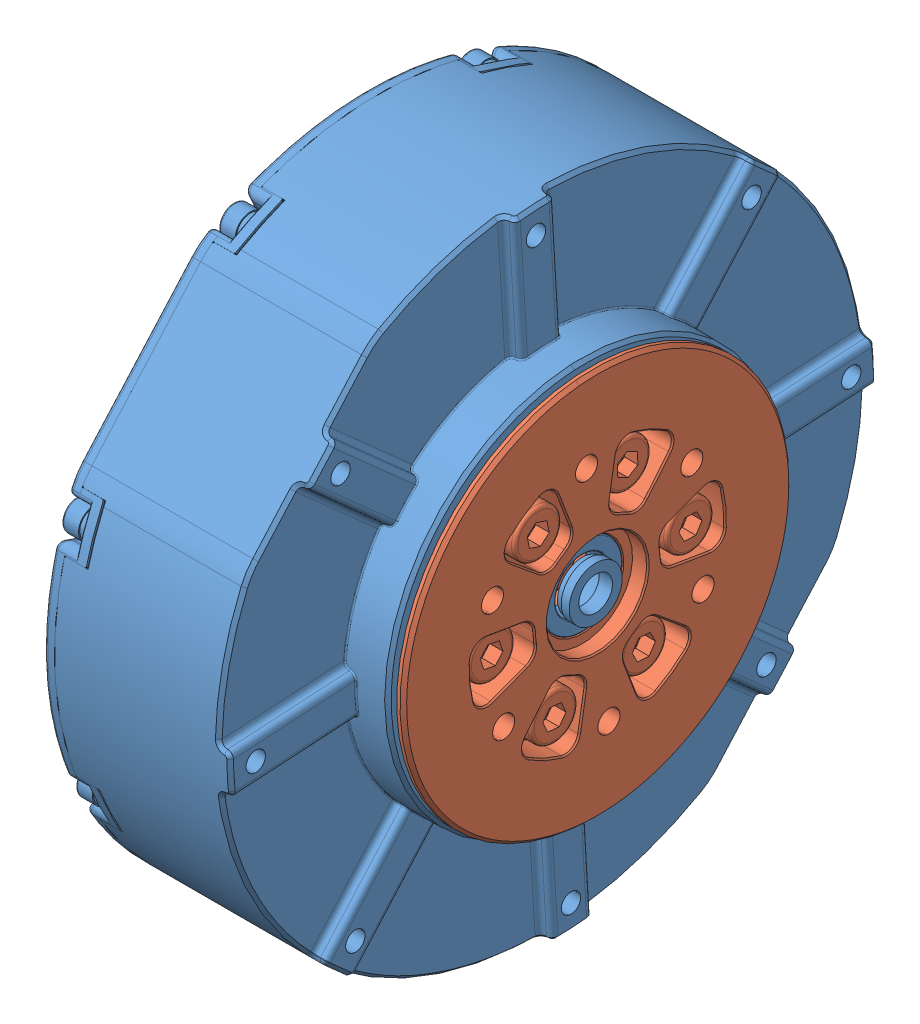
SolidWorks assembly 宇树电机-可转动, configuration 默认. Lengths in mm.
Overall size (42.3 98.68 99.96).
2 component instances, 2 part files, 6 mates.
Components (placement in the parent):
- GO-M8010-6电机3D模型-定子-1: GO-M8010-6电机3D模型-定子 [默认] at origin size (42 98.68 99.96)
- GO-M8010-6电机3D模型-转子-1: GO-M8010-6电机3D模型-转子 [默认] at (105.0963 -178.1437 7.2087) x (1 0 0) z (0 -0.975139 0.221594) size (8.3 59.93 59.79)
Mates (geometry in assembly coordinates):
- 同心1: concentric aligned: circle of GO-M8010-6电机3D模型-定子-1; circle of GO-M8010-6电机3D模型-转子-1
- 距离1: distance = 0.3 mm anti-aligned: plane of GO-M8010-6电机3D模型-定子-1 through (112.4454 -227.1803 -38.815) normal (1 0 0); plane of GO-M8010-6电机3D模型-转子-1 through (112.7454 -135.2106 33.605) normal (-1 0 0)
- 重合4: coincident aligned: plane of GO-M8010-6电机3D模型-定子-1 through (0 0 0) normal (0 0 1)
- 重合5: coincident aligned: plane of GO-M8010-6电机3D模型-定子-1 through (0 0 0) normal (0 1 0)
- 重合6: coincident aligned: plane of GO-M8010-6电机3D模型-定子-1 through (0 0 0) normal (1 0 0)
- 重合7: coordinate: point of GO-M8010-6电机3D模型-定子-1
